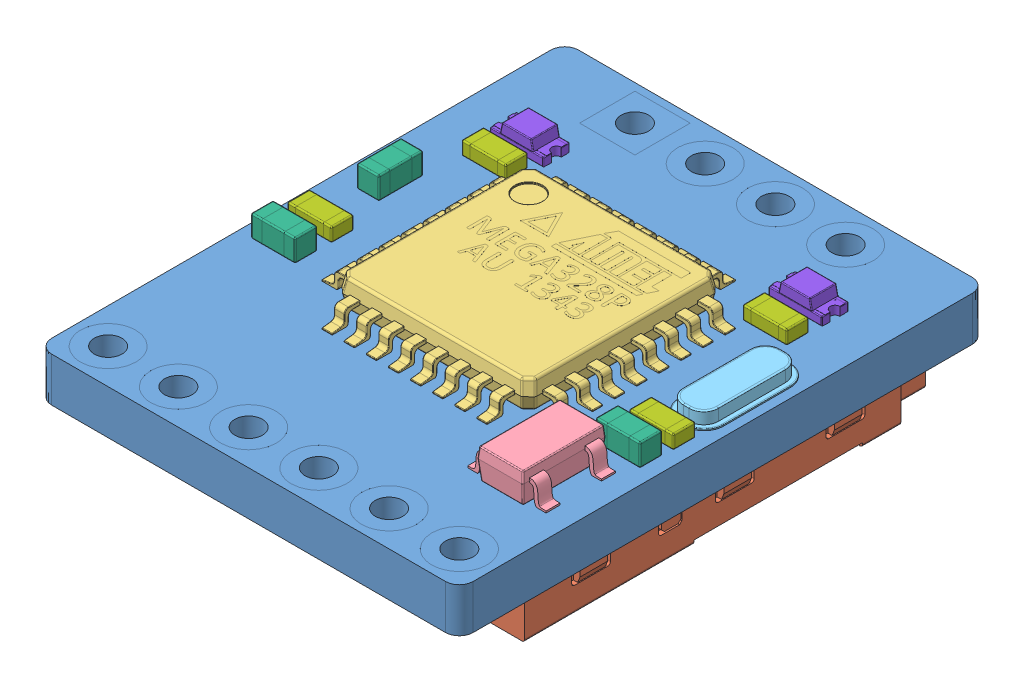
SolidWorks assembly OpenLog - basic, configuration Default. Lengths in mm.
Overall size (15.24 4.55 19.05).
14 component instances, 8 part files, 39 mates.
Components (placement in the parent):
- OpenLog_PCB-1: OpenLog_PCB [Default] at origin size (15.24 1.6 19.05)
- microSDslot.stp-1: microSDslot.stp [Default] at (0.0152 -0.85 -1.0043) x (1 0 0) z (0 -1 0) size (14.1 15.2 1.88)
- ATmega-1: ATmega [Default] at (-0.0317 1.6 -0.6354) size (9 1.1 9)
- SOT23-5-1: SOT23-5 [Default] at (5.3808 1.495 4.313) x (-1 0 0) z (0 1 0) size (2.91 3.01 1.23)
- Fusion001-1: Fusion001 [Default] at (6.4694 1.6 -1.5764) x (0 0 -1) z (0 1 0) size (3.84 1.66 0.85)
- cap_603-1: cap_603 [Default] at (7.1016 2.4 2.4707) x (-1 0 0) z (0 0 1) size (1.6 0.8 0.8)
- res_603-1: res_603 [Default] at (7.1399 2.1 1.3029) x (-1 0 0) z (0 0 1) size (1.6 0.5 0.8)
- cap_603-2: cap_603 [Default] at (-7.1409 1.6 2.3005) size (1.6 0.8 0.8)
- res_603-2: res_603 [Default] at (-5.9255 1.6 -4.0991) size (1.6 0.5 0.8)
- res_603-3: res_603 [Default] at (4.3139 1.6 -4.0229) size (1.6 0.5 0.8)
- res_603-4: res_603 [Default] at (-5.5292 2.1 0.9961) x (-1 0 0) z (0 0 1) size (1.6 0.5 0.8)
- Surface Mount Chip LED 3.2x1.6mm-1: Surface Mount Chip LED 3.2x1.6mm [Default] at (4.0264 1.606 -5.2554) x (1 0 0) z (0 1 0) size (1.92 0.96 0.72)
- Surface Mount Chip LED 3.2x1.6mm-2: Surface Mount Chip LED 3.2x1.6mm [Default] at (-4.0759 1.606 -6.1626) x (-1 0 0) z (0 1 0) size (1.92 0.96 0.72)
- cap_603-3: cap_603 [Default] at (-6.7814 2.4 -1.167) x (0 0 -1) z (-1 0 0) size (1.6 0.8 0.8)
Mates (geometry in assembly coordinates):
- Coincident1: coincident aligned: plane of OpenLog_PCB-1 through (0 0 0) normal (0 0 1)
- Coincident3: coincident aligned: plane of OpenLog_PCB-1 through (0 0 0) normal (1 0 0)
- Coincident4: coincident aligned: plane of OpenLog_PCB-1 through (0 0 0) normal (0 1 0)
- Coincident8: coincident anti-aligned: plane of OpenLog_PCB-1 through (0 0 0) normal (0 -1 0); plane of microSDslot.stp-1 through (0.0152 0 -1.0043) normal (0 1 0)
- Coincident9: coincident anti-aligned: plane of OpenLog_PCB-1 through (0 1.6 0) normal (0 1 0); plane of ATmega-1 through (-0.0317 1.6 -0.6354) normal (0 -1 0)
- Coincident11: coincident anti-aligned: plane of OpenLog_PCB-1 through (0 1.6 0) normal (0 1 0); plane of SOT23-5-1 through (4.6183 1.6 2.813) normal (0 -1 0)
- Parallel3: parallel anti-aligned: line of SOT23-5-1 through (4.5557 2.3233 2.8628) axis (0 0 1); line of OpenLog_PCB-1 through (7.62 1.6 9.025) axis (0 0 -1)
- Coincident13: coincident anti-aligned: plane of OpenLog_PCB-1 through (0 1.6 0) normal (0 1 0); plane of Fusion001-1 through (5.6557 1.6 0.3311) normal (0 -1 0)
- Parallel4: parallel anti-aligned: plane of OpenLog_PCB-1 through (7.62 1.6 -9.525) normal (1 0 0); plane of Fusion001-1 through (5.8394 1.66 0.1649) normal (-1 0 0)
- Coincident15: coincident anti-aligned: plane of OpenLog_PCB-1 through (0 1.6 0) normal (0 1 0); plane of cap_603-1 through (7.1016 1.6 2.4707) normal (0 -1 0)
- Parallel5: parallel aligned: plane of OpenLog_PCB-1 through (-7.62 1.6 -9.525) normal (-1 0 0); plane of cap_603-1 through (5.5016 1.6 1.6707) normal (-1 0 0)
- Coincident17: coincident anti-aligned: plane of OpenLog_PCB-1 through (0 1.6 0) normal (0 1 0); plane of res_603-1 through (7.1399 1.6 1.3029) normal (0 -1 0)
- Parallel6: parallel aligned: plane of OpenLog_PCB-1 through (-7.62 1.6 -9.525) normal (-1 0 0); plane of res_603-1 through (5.5399 1.6 0.5029) normal (-1 0 0)
- Coincident191: coincident anti-aligned: plane of OpenLog_PCB-1 through (0 1.6 0) normal (0 1 0); plane of cap_603-2 through (-7.1409 1.6 2.3005) normal (0 -1 0)
- Coincident201: coincident anti-aligned: plane of OpenLog_PCB-1 through (0 1.6 0) normal (0 1 0); plane of res_603-2 through (-5.9255 1.6 -4.0991) normal (0 -1 0)
- Parallel7: parallel aligned: plane of OpenLog_PCB-1 through (-7.62 1.6 -9.525) normal (-1 0 0); plane of res_603-2 through (-5.9255 2.1 -4.0991) normal (-1 0 0)
- Parallel8: parallel aligned: plane of OpenLog_PCB-1 through (-7.62 1.6 -9.525) normal (-1 0 0); plane of cap_603-2 through (-7.1409 2.4 2.3005) normal (-1 0 0)
- Lock1: lock: unknown of OpenLog_PCB-1; unknown of ATmega-1
- Coincident261: coincident anti-aligned: plane of OpenLog_PCB-1 through (0 1.6 0) normal (0 1 0); plane of res_603-4 through (-5.5292 1.6 0.9961) normal (0 -1 0)
- Parallel10: parallel aligned: plane of OpenLog_PCB-1 through (-7.62 1.6 -9.525) normal (-1 0 0); plane of res_603-4 through (-7.1292 1.6 0.1961) normal (-1 0 0)
- Coincident28: coincident anti-aligned: plane of OpenLog_PCB-1 through (0 1.6 0) normal (0 1 0); plane of Surface Mount Chip LED 3.2x1.6mm-1 through (4.8664 1.6 -6.2154) normal (0 -1 0)
- Parallel12: parallel aligned: plane of OpenLog_PCB-1 through (-7.62 1.6 -9.525) normal (-1 0 0); plane of Surface Mount Chip LED 3.2x1.6mm-2 through (-5.9959 1.606 -6.1626) normal (-1 0 0)
- Coincident31: coincident anti-aligned: plane of OpenLog_PCB-1 through (0 1.6 0) normal (0 1 0); plane of Surface Mount Chip LED 3.2x1.6mm-2 through (-4.9159 1.6 -5.2026) normal (0 -1 0)
- Coincident321: coincident anti-aligned: plane of OpenLog_PCB-1 through (0 1.6 0) normal (0 1 0); plane of cap_603-3 through (-6.7814 1.6 -1.167) normal (0 -1 0)
- Parallel13: parallel aligned: plane of OpenLog_PCB-1 through (-7.62 1.6 -9.525) normal (0 0 -1); plane of cap_603-3 through (-5.9814 1.6 -2.767) normal (0 0 -1)
- Lock9: lock: unknown of OpenLog_PCB-1; unknown of cap_603-2
- Lock10: lock: unknown of OpenLog_PCB-1; unknown of res_603-4
- Lock11: lock: unknown of OpenLog_PCB-1; unknown of cap_603-3
- Lock12: lock: unknown of OpenLog_PCB-1; unknown of res_603-2
- Lock13: lock: unknown of OpenLog_PCB-1; unknown of Surface Mount Chip LED 3.2x1.6mm-2
- Lock14: lock: unknown of OpenLog_PCB-1; unknown of Surface Mount Chip LED 3.2x1.6mm-1
- Parallel17: parallel anti-aligned: plane of OpenLog_PCB-1 through (0 1.6 0) normal (0 1 0); plane of res_603-3 through (4.3139 1.6 -4.0229) normal (0 -1 0)
- Coincident47: coincident anti-aligned: plane of OpenLog_PCB-1 through (0 1.6 0) normal (0 1 0); plane of res_603-3 through (4.3139 1.6 -4.0229) normal (0 -1 0)
- Lock15: lock: unknown of OpenLog_PCB-1; unknown of res_603-3
- Lock16: lock: unknown of OpenLog_PCB-1; unknown of Fusion001-1
- Lock17: lock: unknown of OpenLog_PCB-1; unknown of res_603-1
- Lock18: lock: unknown of OpenLog_PCB-1; unknown of cap_603-1
- Lock19: lock: unknown of OpenLog_PCB-1; unknown of SOT23-5-1
- Lock21: lock: unknown of OpenLog_PCB-1; unknown of microSDslot.stp-1
